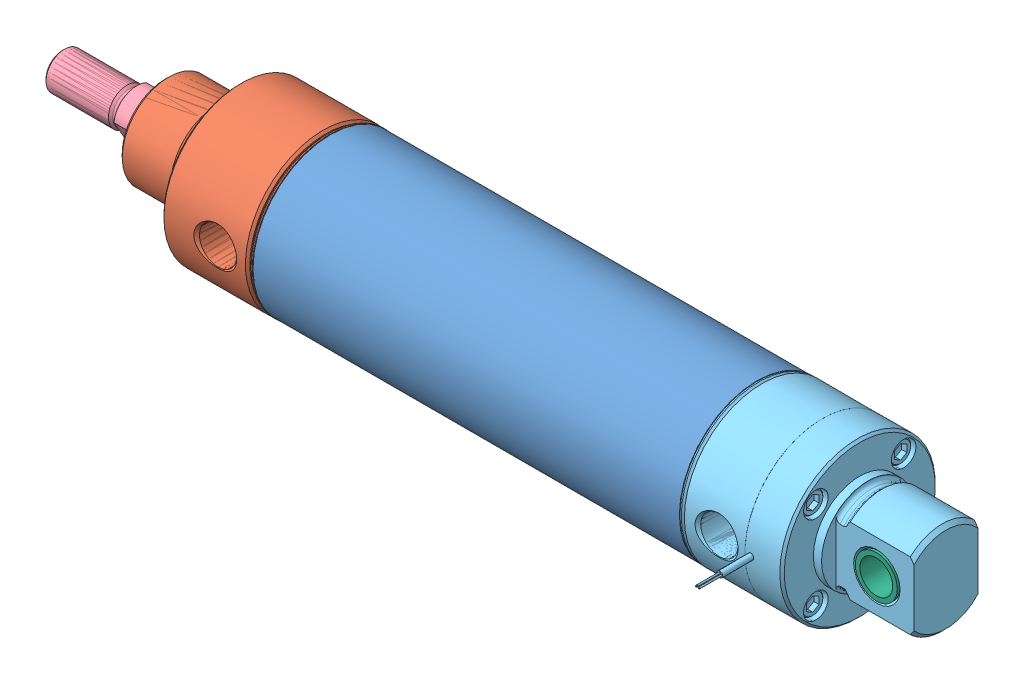
SolidWorks assembly PFC-314-X, configuration Default. Lengths in mm.
Overall size (301.75 53.09 71.29).
7 component instances, 7 part files, 18 mates.
Components (placement in the parent):
- PFC-314-X_0_dummy-1: PFC-314-X_0_dummy [Default] at origin
- PFC-31-4-1: PFC-31-4 [Default] at (130.0734 0 0) size (148.28 52.98 52.98)
- PFC-31X-_0_rod_guide-1: PFC-31X-_0_rod_guide [Default] at (-38.8874 0 0) x (-1 0 0) z (0 0 1) size (64.29 53.09 53.09)
- PFC-314-X__rod-1: PFC-314-X__rod [Default] at (-43.7642 0 0) size (196.06 50.9 50.9)
- PFCN-314-0_31_stud-1: PFCN-314-0_31_stud [Default] at (-43.7642 0 0) x (-1 0 0) z (0 0 1) size (55.58 15.7 15.61)
- PFC-31X-1: PFC-31X [Default] at (172.9486 0 0) size (72.34 53.09 71.29)
- D-8342-XX-1: D-8342-XX [Default] at (189.7126 0 0) x (1 0 0) z (0 0 -1) size (14.35 14.35 22.23)
Mates (geometry in assembly coordinates):
- Distance1: distance = 0 mm anti-aligned: plane of PFC-31-4-1 through (0 0 0) normal (-1 0 0); plane of PFC-314-X_0_dummy-1 through (0 0 0) normal (1 0 0)
- Coincident1: coincident anti-aligned: line of PFC-314-X_0_dummy-1 through (80.9 0 0) axis (-1 0 0); line of PFC-31-4-1 through (49.1734 0 0) axis (1 0 0)
- Angle3: planar angle = 0 rad aligned: plane of PFC-31-4-1 through (130.0734 0 0) normal (0 0 -1); plane of PFC-314-X_0_dummy-1 through (0 0 0) normal (0 0 -1)
- Distance2: distance = 0 mm: plane of PFC-31X-_0_rod_guide-1; plane of PFC-31-4-1 through (0 0 0) normal (1 0 0)
- Coincident2: coincident: line of PFC-31-4-1 through (210.9734 0 0) axis (-1 0 0); line of PFC-31X-_0_rod_guide-1 through (-119.7874 0 0) axis (1 0 0)
- Angle6: planar angle = 0 rad: plane of PFC-31X-_0_rod_guide-1 through (-38.8874 0 0) normal (0 0 -1); plane of PFC-31-4-1 through (130.0734 0 0) normal (0 0 -1)
- LimitDistance1: limit distance = 0 mm: plane of PFC-314-X__rod-1 through (-64.2874 0 0) normal (-1 0 0); plane of PFC-31X-_0_rod_guide-1
- Coincident3: coincident: line of PFC-31X-_0_rod_guide-1 through (42.0126 0 0) axis (-1 0 0); line of PFC-314-X__rod-1 through (-124.6642 0 0) axis (1 0 0)
- Angle9: planar angle = 0 rad: plane of PFC-314-X__rod-1 through (-43.7642 0 0) normal (0 0 -1); plane of PFC-31X-_0_rod_guide-1 through (-38.8874 0 0) normal (0 0 -1)
- Distance3: distance = 0 mm anti-aligned: plane of PFCN-314-0_31_stud-1; plane of PFC-314-X__rod-1 through (-64.2874 0 0) normal (1 0 0)
- Coincident4: coincident anti-aligned: line of PFC-314-X__rod-1 through (37.1358 0 0) axis (-1 0 0); line of PFCN-314-0_31_stud-1 through (-124.6642 0 0) axis (1 0 0)
- Angle12: planar angle = 0 rad aligned: plane of PFCN-314-0_31_stud-1 through (-43.7642 0 0) normal (0 0 -1); plane of PFC-314-X__rod-1 through (-43.7642 0 0) normal (0 0 -1)
- Distance4: distance = 0 mm: plane of PFC-31X-1 through (130.0734 0 0) normal (1 0 0); plane of PFC-31-4-1 through (130.0734 0 0) normal (-1 0 0)
- Coincident5: coincident: line of PFC-31-4-1 through (49.1734 0 0) axis (1 0 0); line of PFC-31X-1 through (253.8486 0 0) axis (-1 0 0)
- Angle15: planar angle = 0 rad: plane of PFC-31X-1 through (172.9486 0 0) normal (0 0 -1); plane of PFC-31-4-1 through (130.0734 0 0) normal (0 0 -1)
- Distance5: distance = 0 mm: plane of D-8342-XX-1 through (189.7126 0 0) normal (0 0 -1); plane of PFC-31X-1 through (172.9486 0 0) normal (0 0 1)
- Coincident6: coincident: line of PFC-31X-1 through (189.7126 0 80.9) axis (0 0 -1); line of D-8342-XX-1 through (189.7126 0 -80.9) axis (0 0 1)
- Angle18: planar angle = 0 rad: plane of D-8342-XX-1; plane of PFC-31X-1 through (189.7126 0 0) normal (1 0 0)
